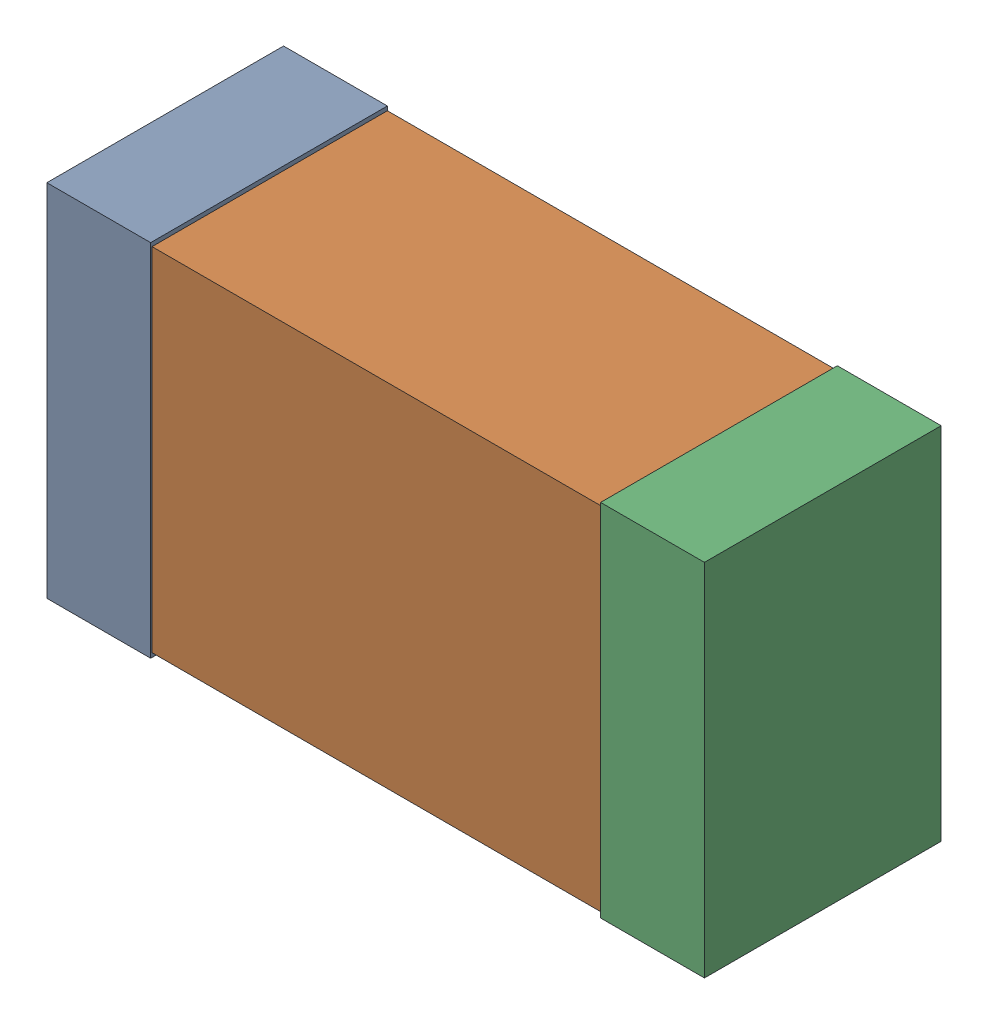
SolidWorks assembly C9_0Kanaloa_v2.0.0_Motor, configuration Default. Lengths in mm.
Overall size (2.38 1.3 0.85).
6 component instances, 2 part files, 0 mates.
Components (placement in the parent):
- 352877648-1: 352877648 [Default] at (33.993 50.292 0) size (0.38 1.3 0.85)
  - Extruded_14-1: Extruded_14 [Default] at origin size (0.38 1.3 0.85)
- 352877392-1: 352877392 [Default] at (34.993 50.292 0) size (2.2 1.27 0.85)
  - Extruded_15-1: Extruded_15 [Default] at origin size (2.2 1.27 0.85)
- 352877648-2: 352877648 [Default] at (35.993 50.292 0) size (0.38 1.3 0.85)
  - Extruded_14-1: Extruded_14 [Default] at origin size (0.38 1.3 0.85)
